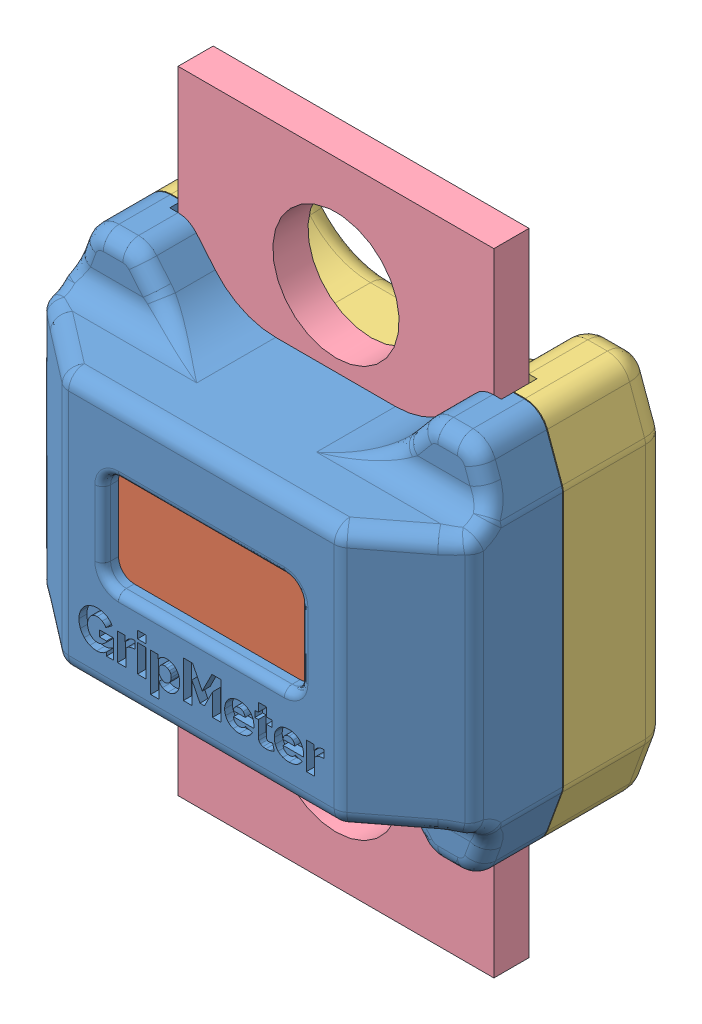
SolidWorks assembly Ensamblaje_Gripmeter_Slim_Trunks, configuration Predeterminado. Lengths in mm.
Overall size (56.5 80 32.23).
94 component instances, 22 part files, 11 mates.
Components (placement in the parent):
- GripMeter_Slim_Trunks_Front-1: GripMeter_Slim_Trunks_Front [Predeterminado] at (-13.3216 0.3066 60.7569) size (56.5 48 18.5)
- GripMeter_PCB-1: GripMeter_PCB [Predeterminado] at (-138.6124 -138.551 53.2569) x (1 0 0) z (0 0 -1) size (53.88 25 9.73)
  - User_Library-SK-22D02-PG4-1: User_Library-SK-22D02-PG4 [Predeterminado] at (103.17 -135.39 1.65) x (0 1 0) z (0 0 1) size (10.4 10.1 7.6)
    - COMPOUND-1: COMPOUND [Predeterminado] at origin size (10.4 10.1 7.6)
  - SOP-16_4.4x10.4mm_P1.27mm-1: SOP-16_4.4x10.4mm_P1.27mm [Predeterminado] at (120.83 -135.77 1.65) x (0 1 0) z (0 0 1) size (6.4 10.4 2.1)
    - SOLID-1: SOLID [Predeterminado] at origin size (6.4 10.4 2.1)
  - df13-2p-1_25ds_50_-1: df13-2p-1_25ds_50_ [Predeterminado] at (98.16 -128.54 28.65) x (0 0 1) z (-1 0 0) size (5.9 5.4 4.15)
    - COMPOUND_2-1: COMPOUND_2 [Predeterminado] at origin size (5.9 5.4 4.15)
  - D_SOD-123F-1: D_SOD-123F [Predeterminado] at (141.02 -136.69 1.65) size (3.5 1.6 1.1)
    - SOLID_2-1: SOLID_2 [Predeterminado] at origin size (3.5 1.6 1.1)
  - df13-4p-1_25ds_50_-1: df13-4p-1_25ds_50_ [Predeterminado] at (132.8 -146.68 29.15) x (0 0 1) z (1 0 0) size (5.9 5.4 6.65)
    - COMPOUND_3-1: COMPOUND_3 [Predeterminado] at origin size (5.9 5.4 6.65)
  - df13-4p-1_25ds_50_-2: df13-4p-1_25ds_50_ [Predeterminado] at (105.5 -128.48 29.15) x (0 0 1) z (-1 0 0) size (5.9 5.4 6.65)
    - COMPOUND_3-1: COMPOUND_3 [Predeterminado] at origin size (5.9 5.4 6.65)
  - SOP-16_4.4x10.4mm_P1.27mm-2: SOP-16_4.4x10.4mm_P1.27mm [Predeterminado] at (135.86 -143.9 1.65) size (6.4 10.4 2.1)
    - SOLID-1: SOLID [Predeterminado] at origin size (6.4 10.4 2.1)
  - SOT-23-5-1: SOT-23-5 [Predeterminado] at (109.15 -129.05 1.65) x (-1 0 0) z (0 0 1) size (2.8 2.9 1.55)
    - SOLID_3-1: SOLID_3 [Predeterminado] at origin size (2.8 2.9 1.55)
  - SOT-223-1: SOT-223 [Predeterminado] at (129.92 -133.71 1.65) x (0 -1 0) z (0 0 1) size (7 6.5 1.7)
    - SOLID_4-1: SOLID_4 [Predeterminado] at origin size (7 6.5 1.7)
  - R_0603_1608Metric-1: R_0603_1608Metric [Predeterminado] at (104.5 -126.34 1.65) size (1.6 0.8 0.45)
    - SOLID_5-1: SOLID_5 [Predeterminado] at origin size (1.6 0.8 0.45)
  - R_0603_1608Metric-2: R_0603_1608Metric [Predeterminado] at (134.25 -136.63 1.65) x (0 1 0) z (0 0 1) size (1.6 0.8 0.45)
    - SOLID_5-1: SOLID_5 [Predeterminado] at origin size (1.6 0.8 0.45)
  - R_0603_1608Metric-3: R_0603_1608Metric [Predeterminado] at (122.06 -142.08 1.65) size (1.6 0.8 0.45)
    - SOLID_5-1: SOLID_5 [Predeterminado] at origin size (1.6 0.8 0.45)
  - R_0603_1608Metric-4: R_0603_1608Metric [Predeterminado] at (119.075 -140.6 1.65) size (1.6 0.8 0.45)
    - SOLID_5-1: SOLID_5 [Predeterminado] at origin size (1.6 0.8 0.45)
  - R_0603_1608Metric-5: R_0603_1608Metric [Predeterminado] at (125.86 -142.8 1.65) x (0 -1 0) z (0 0 1) size (1.6 0.8 0.45)
    - SOLID_5-1: SOLID_5 [Predeterminado] at origin size (1.6 0.8 0.45)
  - R_0603_1608Metric-6: R_0603_1608Metric [Predeterminado] at (124.3 -142.84 1.65) x (0 -1 0) z (0 0 1) size (1.6 0.8 0.45)
    - SOLID_5-1: SOLID_5 [Predeterminado] at origin size (1.6 0.8 0.45)
  - R_0603_1608Metric-7: R_0603_1608Metric [Predeterminado] at (130.25 -148.14 1.65) x (-1 0 0) z (0 0 1) size (1.6 0.8 0.45)
    - SOLID_5-1: SOLID_5 [Predeterminado] at origin size (1.6 0.8 0.45)
  - R_0603_1608Metric-8: R_0603_1608Metric [Predeterminado] at (130.25 -146.68 1.65) size (1.6 0.8 0.45)
    - SOLID_5-1: SOLID_5 [Predeterminado] at origin size (1.6 0.8 0.45)
  - R_0603_1608Metric-9: R_0603_1608Metric [Predeterminado] at (110.57 -144.55 1.65) x (-1 0 0) z (0 0 1) size (1.6 0.8 0.45)
    - SOLID_5-1: SOLID_5 [Predeterminado] at origin size (1.6 0.8 0.45)
  - R_0603_1608Metric-10: R_0603_1608Metric [Predeterminado] at (104.9 -128.1 1.65) x (-1 0 0) z (0 0 1) size (1.6 0.8 0.45)
    - SOLID_5-1: SOLID_5 [Predeterminado] at origin size (1.6 0.8 0.45)
  - R_0603_1608Metric-11: R_0603_1608Metric [Predeterminado] at (108.7 -126.35 1.65) size (1.6 0.8 0.45)
    - SOLID_5-1: SOLID_5 [Predeterminado] at origin size (1.6 0.8 0.45)
  - R_0603_1608Metric-12: R_0603_1608Metric [Predeterminado] at (142.59 -144.46 1.65) x (0 -1 0) z (0 0 1) size (1.6 0.8 0.45)
    - SOLID_5-1: SOLID_5 [Predeterminado] at origin size (1.6 0.8 0.45)
  - R_0603_1608Metric-13: R_0603_1608Metric [Predeterminado] at (141.425 -138.75 1.65) x (-1 0 0) z (0 0 1) size (1.6 0.8 0.45)
    - SOLID_5-1: SOLID_5 [Predeterminado] at origin size (1.6 0.8 0.45)
  - R_0603_1608Metric-14: R_0603_1608Metric [Predeterminado] at (145.09 -126.72 1.65) size (1.6 0.8 0.45)
    - SOLID_5-1: SOLID_5 [Predeterminado] at origin size (1.6 0.8 0.45)
  - R_0603_1608Metric-15: R_0603_1608Metric [Predeterminado] at (140.93 -144.46 1.65) x (0 -1 0) z (0 0 1) size (1.6 0.8 0.45)
    - SOLID_5-1: SOLID_5 [Predeterminado] at origin size (1.6 0.8 0.45)
  - SOT-23-1: SOT-23 [Predeterminado] at (136.76 -136.63 1.65) size (2.5 3 1.2)
    - SOLID_6-1: SOLID_6 [Predeterminado] at origin size (2.5 3 1.2)
  - SOT-23-2: SOT-23 [Predeterminado] at (115.26 -141.56 1.65) x (0 -1 0) z (0 0 1) size (2.5 3 1.2)
    - SOLID_6-1: SOLID_6 [Predeterminado] at origin size (2.5 3 1.2)
  - SOT-23-3: SOT-23 [Predeterminado] at (112.57 -147.03 1.65) size (2.5 3 1.2)
    - SOLID_6-1: SOLID_6 [Predeterminado] at origin size (2.5 3 1.2)
  - SOT-23-4: SOT-23 [Predeterminado] at (141.66 -147.65 1.65) x (0 -1 0) z (0 0 1) size (2.5 3 1.2)
    - SOLID_6-1: SOLID_6 [Predeterminado] at origin size (2.5 3 1.2)
  - SOT-23-5: SOT-23 [Predeterminado] at (141.62 -141.23 1.65) size (2.5 3 1.2)
    - SOLID_6-1: SOLID_6 [Predeterminado] at origin size (2.5 3 1.2)
  - LED_0603_1608Metric-1: LED_0603_1608Metric [Predeterminado] at (101.54 -126.32 1.65) x (-1 0 0) z (0 0 1) size (1.6 0.8 1.1)
    - SOLID_7-1: SOLID_7 [Predeterminado] at origin size (1.6 0.8 1.1)
  - LED_0603_1608Metric-2: LED_0603_1608Metric [Predeterminado] at (148.09 -126.72 1.65) x (-1 0 0) z (0 0 1) size (1.6 0.8 1.1)
    - SOLID_7-1: SOLID_7 [Predeterminado] at origin size (1.6 0.8 1.1)
  - D_SOD-123-1: D_SOD-123 [Predeterminado] at (107.7 -146.39 1.65) x (0 1 0) z (0 0 1) size (3.8 1.6 1.25)
    - SOLID_8-1: SOLID_8 [Predeterminado] at origin size (3.8 1.6 1.25)
  - LED_0805_2012Metric-1: LED_0805_2012Metric [Predeterminado] at (101.72 -128.32 1.65) size (2 1.25 1.1)
    - SOLID_9-1: SOLID_9 [Predeterminado] at origin size (2 1.25 1.1)
  - C_0805_2012Metric-1: C_0805_2012Metric [Predeterminado] at (114.38 -137.23 1.65) x (0 1 0) z (0 0 1) size (2 1.25 1.25)
    - SOLID_10-1: SOLID_10 [Predeterminado] at origin size (2 1.25 1.25)
  - C_0603_1608Metric-1: C_0603_1608Metric [Predeterminado] at (125.13 -140.58 1.65) size (1.6 0.8 0.8)
    - SOLID_11-1: SOLID_11 [Predeterminado] at origin size (1.6 0.8 0.8)
  - C_0603_1608Metric-2: C_0603_1608Metric [Predeterminado] at (122.13 -140.57 1.65) size (1.6 0.8 0.8)
    - SOLID_11-1: SOLID_11 [Predeterminado] at origin size (1.6 0.8 0.8)
  - C_0805_2012Metric-2: C_0805_2012Metric [Predeterminado] at (118.81 -142.41 1.65) size (2 1.25 1.25)
    - SOLID_10-1: SOLID_10 [Predeterminado] at origin size (2 1.25 1.25)
  - C_0603_1608Metric-3: C_0603_1608Metric [Predeterminado] at (131.61 -126.52 1.65) size (1.6 0.8 0.8)
    - SOLID_11-1: SOLID_11 [Predeterminado] at origin size (1.6 0.8 0.8)
  - C_0805_2012Metric-3: C_0805_2012Metric [Predeterminado] at (131.83 -128.25 1.65) size (2 1.25 1.25)
    - SOLID_10-1: SOLID_10 [Predeterminado] at origin size (2 1.25 1.25)
  - C_0805_2012Metric-4: C_0805_2012Metric [Predeterminado] at (109.85 -147.04 1.65) x (0 1 0) z (0 0 1) size (2 1.25 1.25)
    - SOLID_10-1: SOLID_10 [Predeterminado] at origin size (2 1.25 1.25)
  - C_0805_2012Metric-5: C_0805_2012Metric [Predeterminado] at (127.78 -147.43 1.65) x (0 -1 0) z (0 0 1) size (2 1.25 1.25)
    - SOLID_10-1: SOLID_10 [Predeterminado] at origin size (2 1.25 1.25)
  - Micro_USB-B_Female_5Pin_SMD-1: Micro_USB-B_Female_5Pin_SMD [Predeterminado] at (104.29 -145.58 2.9) x (0 -1 0) z (-1 0 0) size (8.05 3.73 5.8)
    - COMPOUND_4-1: COMPOUND_4 [Predeterminado] at origin size (8.05 3.73 5.8)
  - User_Library-ESP321-1: User_Library-ESP321 [Predeterminado] at (137.2 -137 -0.05) x (0 1 0) z (0 0 -1) size (18 25.5 2.95)
    - COMPOUND_5-1: COMPOUND_5 [Predeterminado] at origin size (18 25.5 2.95)
  - User_Library-YX7525P-1: User_Library-YX7525P [Predeterminado] at (138.6 -129.83 1.65) size (7.56 7.56 2.51)
    - SOLID_12-1: SOLID_12 [Predeterminado] at origin size (7.56 7.56 2.51)
  - COMPOUND_6-1: COMPOUND_6 [Predeterminado] at origin size (50 25 1.6)
- OLED .96 128x64 -2: OLED .96 128x64  [Default] at (-13.4716 -1.5684 57.2569) x (-1 0 0) z (0 0 -1) size (27.3 27.75 5.8)
- GripMeter_Slim_Trunks_Back-1: GripMeter_Slim_Trunks_Back [Predeterminado] at (-13.3216 -0.9434 32.2569) size (54.5 48 15.23)
- Scale_sensor-1: Scale_sensor [Predeterminado] at (-13.3216 -2.1934 45.7069) x (1 0 0) z (0 1 0) size (40 4.45 80)
Mates (geometry in assembly coordinates):
- Coincidente1: coincident anti-aligned: plane of GripMeter_Slim_Trunks_Front-1 through (-13.3216 0.3066 53.2569) normal (0 0 -1); plane of GripMeter_PCB-1/COMPOUND_6-1 through (-13.6124 -1.051 53.2569) normal (0 0 1)
- Paralelo1: parallel anti-aligned: plane of GripMeter_Slim_Trunks_Front-1 through (3.9284 -13.6934 51.2569) normal (0 1 0); plane of GripMeter_PCB-1/COMPOUND_6-1 through (-38.6124 -13.551 53.2569) normal (0 -1 0)
- Coincidente4: coincident anti-aligned: plane of GripMeter_Slim_Trunks_Front-1 through (-13.3216 0.3066 60.7569) normal (0 0 -1); plane of OLED .96 128x64 -2 through (-13.4716 -1.5684 60.7569) normal (0 0 1)
- Coincidente8: coincident anti-aligned: plane of GripMeter_Slim_Trunks_Front-1 through (0.1784 8.5566 58.7569) normal (0 -1 0); plane of OLED .96 128x64 -2 through (-0.1216 8.5566 60.7569) normal (0 1 0)
- Coincidente9: coincident anti-aligned: plane of GripMeter_Slim_Trunks_Front-1 through (-26.8216 -11.4434 58.7569) normal (1 0 0); plane of OLED .96 128x64 -2 through (-26.8216 8.5566 60.7569) normal (-1 0 0)
- Coincidente10: coincident: plane of GripMeter_Slim_Trunks_Front-1 through (-13.3216 0.3066 45.7569) normal (0 0 -1); plane of GripMeter_Slim_Trunks_Back-1 through (6.6784 -20.9434 45.7569) normal (0 0 1)
- Concéntrica1: concentric: cylinder of GripMeter_Slim_Trunks_Front-1 through (8.9284 15.8066 52.2569) axis (0 0 -1) radius 1.25; cylinder of GripMeter_Slim_Trunks_Back-1 through (8.9284 15.8066 30.7569) axis (0 0 1) radius 1.5
- Concéntrica2: concentric anti-aligned: cylinder of GripMeter_Slim_Trunks_Front-1 through (-35.5716 -17.6934 52.2569) axis (0 0 -1) radius 1.25; cylinder of GripMeter_Slim_Trunks_Back-1 through (-35.5716 -17.6934 30.7569) axis (0 0 1) radius 1.5
- Coincidente11: coincident: plane of GripMeter_Slim_Trunks_Back-1 through (-35.7412 20.0566 41.2569) normal (0 0 1); plane of Scale_sensor-1 through (-40.9885 -11.4042 41.2569) normal (0 0 -1)
- Concéntrica3: concentric: cylinder of GripMeter_Slim_Trunks_Back-1 through (6.6784 19.0566 45.7569) axis (0 0 -1) radius 2.5; cylinder of Scale_sensor-1 through (6.6784 19.0566 41.2569) axis (0 0 1) radius 3
- Concéntrica4: concentric anti-aligned: cylinder of GripMeter_Slim_Trunks_Back-1 through (-33.3216 19.0566 45.7569) axis (0 0 -1) radius 2.5; cylinder of Scale_sensor-1 through (-33.3216 19.0566 41.2569) axis (0 0 1) radius 3
